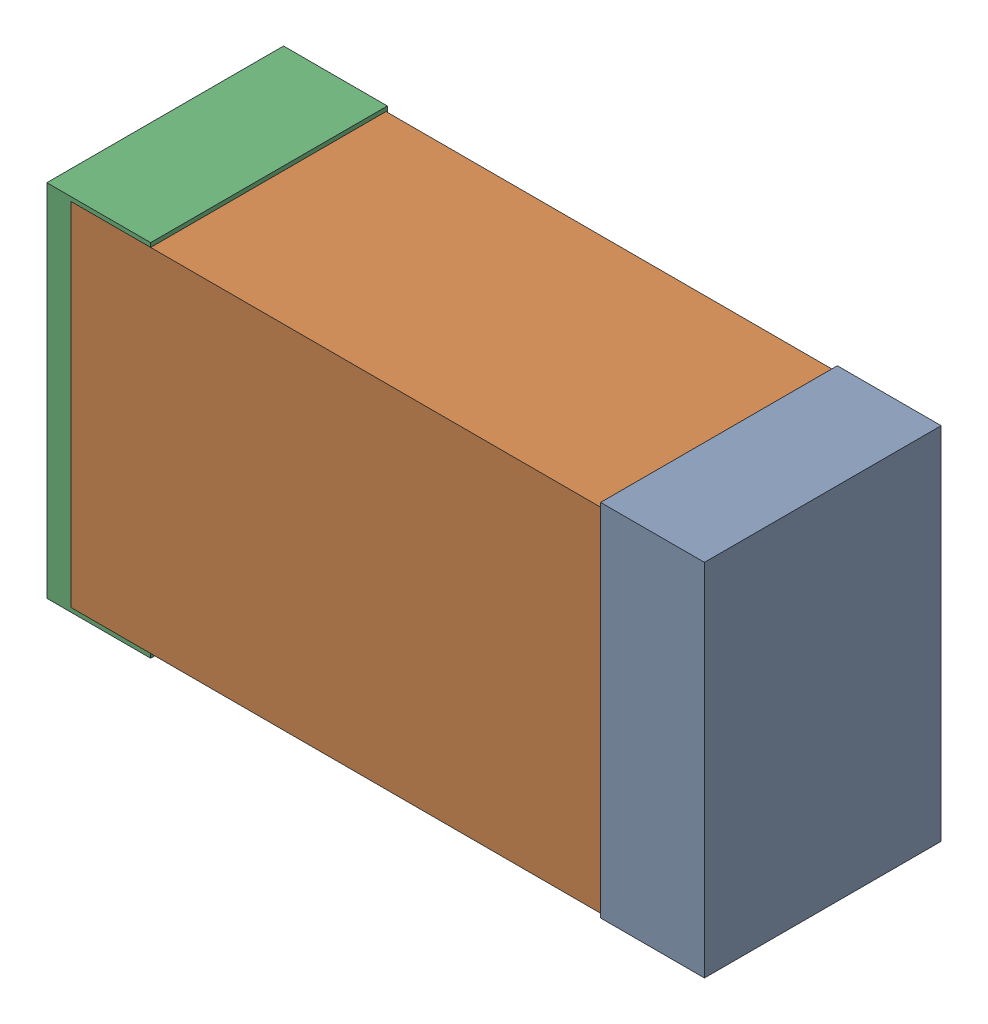
SolidWorks assembly USB67_C8, configuration Default. Lengths in mm.
Overall size (2.38 1.3 0.85).
6 component instances, 2 part files, 0 mates.
Components (placement in the parent):
- 384311232-1: 384311232 [Default] at (146.229 90.043 -1.9574) size (0.38 1.3 0.85)
  - Extruded_8-1: Extruded_8 [Default] at origin size (0.38 1.3 0.85)
- 402662800-1: 402662800 [Default] at (145.229 90.043 -1.9524) size (2.2 1.27 0.85)
  - Extruded_30-1: Extruded_30 [Default] at origin size (2.2 1.27 0.85)
- 384311232-2: 384311232 [Default] at (144.229 90.043 -1.9574) size (0.38 1.3 0.85)
  - Extruded_8-1: Extruded_8 [Default] at origin size (0.38 1.3 0.85)
